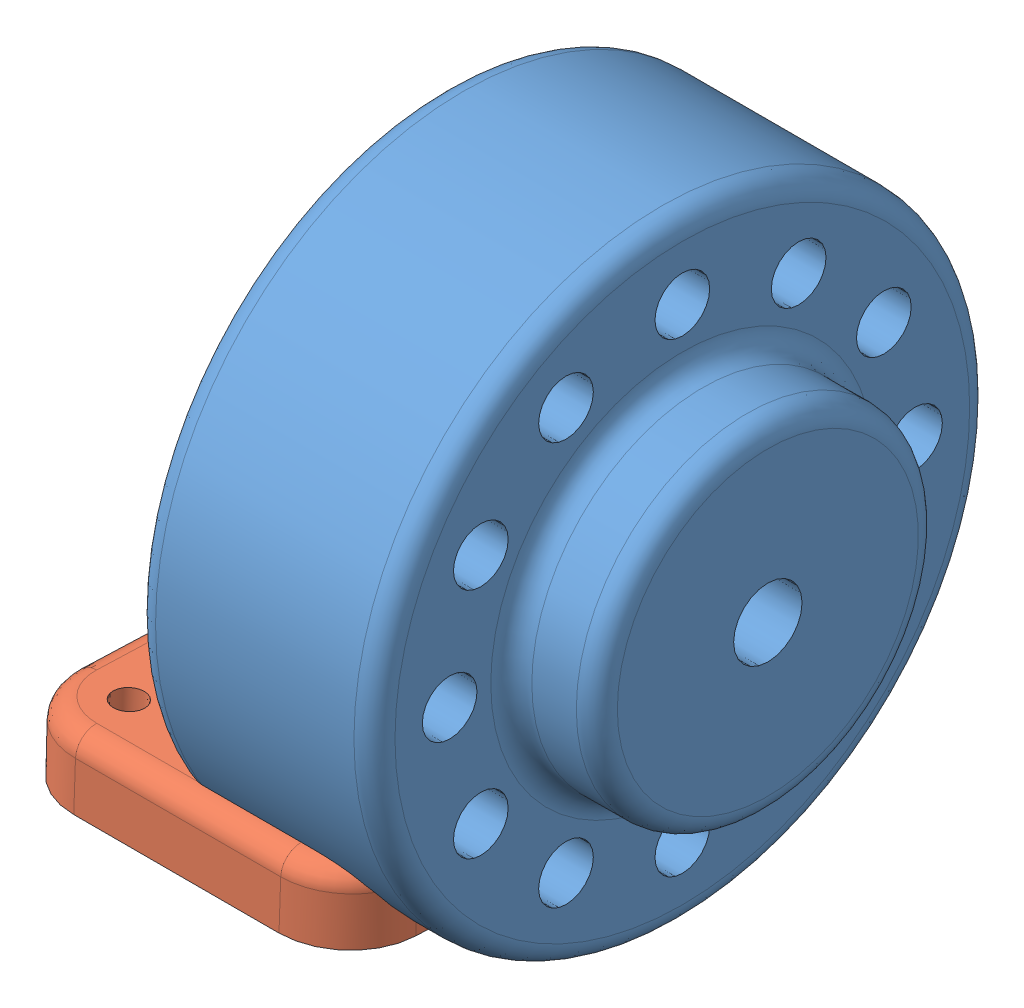
SolidWorks assembly Assem1, configuration Default. Lengths in mm.
Overall size (70 90 90).
2 component instances, 2 part files, 2 mates.
Components (placement in the parent):
- t7-1: t7 [Default] at (23.008 48.9588 73.3159) size (60 90 90)
- T-1: T [Default] at (8.008 12.498 34.8182) x (0 0.035895 0.999356) z (-1 0 0) size (80 45.68 50)
Mates (geometry in assembly coordinates):
- Concentric1: concentric aligned: circle of t7-1; circle of T-1
- Coincident4: coincident anti-aligned: plane of t7-1 through (-6.992 70.9588 73.3159) normal (-1 0 0); plane of T-1 through (-6.992 49.5919 73.5116) normal (1 0 0)
